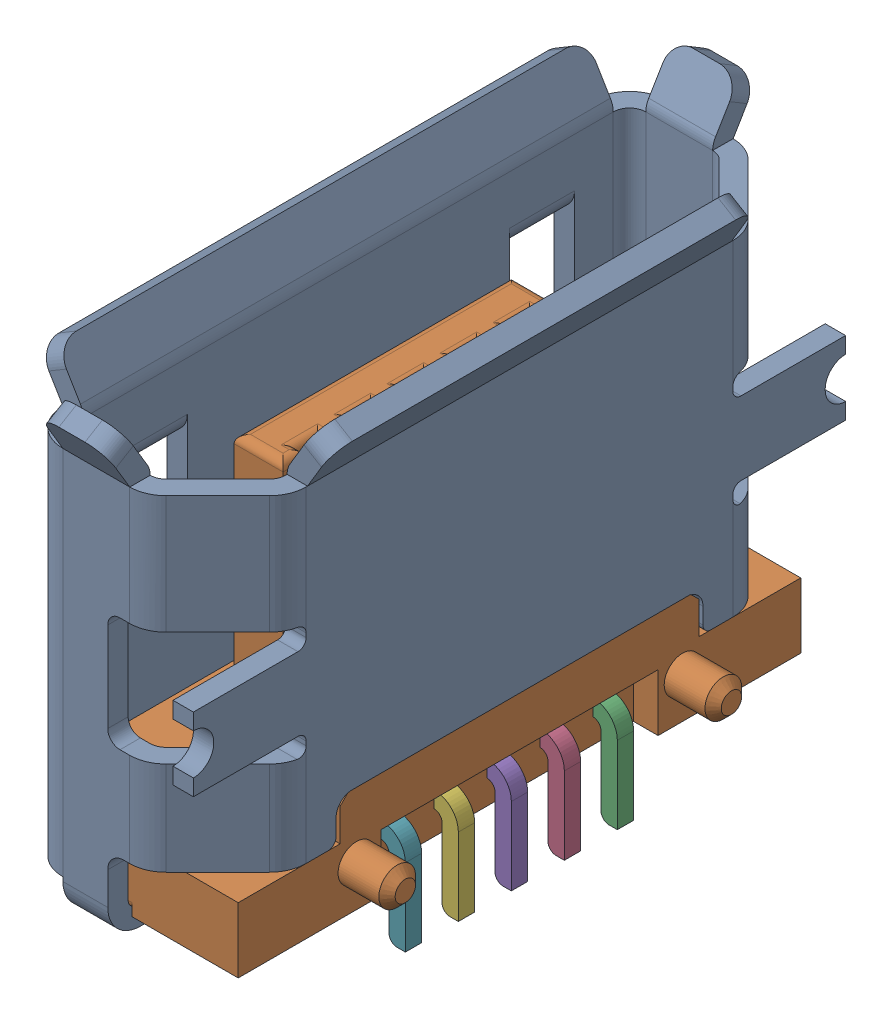
SolidWorks assembly micro usb v1, configuration Default. Lengths in mm.
Overall size (3.25 6.18 8.01).
7 component instances, 3 part files, 0 mates.
Components (placement in the parent):
- micro usb shell-1: micro usb shell [Default] at (10.11 -1.95 -0.7124) x (0 0 -1) z (0 1 0) size (8.01 2.95 5.63)
- micro usb internal-1: micro usb internal [Default] at (10.36 -1.95 -0.7124) x (0 0 -1) z (0 1 0) size (6.9 2.9 4)
- micro usb contact-1: micro usb contact [Default] at (10.36 -2.05 -2.0124) x (0 0 -1) z (0 1 0) size (0.2 1.3 4.65)
- micro usb contact-2: micro usb contact [Default] at (10.36 -2.05 -1.3624) x (0 0 -1) z (0 1 0) size (0.2 1.3 4.65)
- micro usb contact-3: micro usb contact [Default] at (10.36 -2.05 -0.7124) x (0 0 -1) z (0 1 0) size (0.2 1.3 4.65)
- micro usb contact-4: micro usb contact [Default] at (10.36 -2.05 -0.0624) x (0 0 -1) z (0 1 0) size (0.2 1.3 4.65)
- micro usb contact-5: micro usb contact [Default] at (10.36 -2.05 0.5876) x (0 0 -1) z (0 1 0) size (0.2 1.3 4.65)
